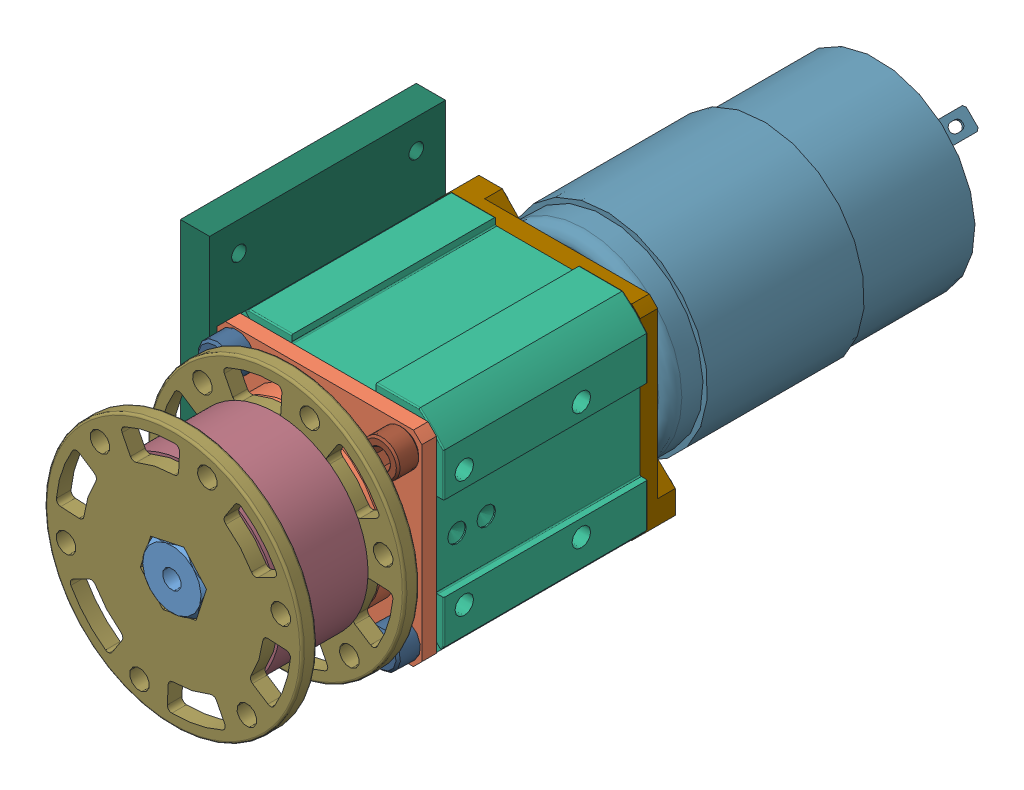
SolidWorks assembly 40-502 Ramp Motor Asm, configuration Default. Lengths in mm.
Overall size (70.41 73.03 162.19).
25 component instances, 15 part files, 20 mates.
Components (placement in the parent):
- 40-501-16 to 1- 57 Sport-1: 40-501-16 to 1- 57 Sport [Default] at (-0.3401 43.5599 88.1883) size (47.68 47.68 89.15) (flexible)
  - am-XXXX - 57 Sport 500 Hex Output Plug-1: am-XXXX - 57 Sport 500 Hex Output Plug [Default] at (20.4435 33.6564 37.638) size (44.45 44.45 56.9) (flexible)
    - am-XXXX - 57 Sport 500 Hex Shaft-1: am-XXXX - 57 Sport 500 Hex Shaft [Default] at (0 0 6.2738) x (0.669193 -0.743089 0) z (0 0 1) size (16.1 12.67 56.9)
    - Output Block-1: Output Block [Default] at origin size (44.45 44.45 20.32)
    - FR8ZZ Bearing-1: FR8ZZ Bearing [Default] at (8.9053 -5.9773 -13.8938) x (0.999973 0.007281 0) z (0 0 1) size (31.75 31.75 7.95)
    - FR8ZZ Bearing-2: FR8ZZ Bearing [Default] at (5.8713 8.9755 6.2738) x (0.923728 0.383049 0) z (0 0 -1) size (31.75 31.75 7.95)
    - retaining Ring 0500 - Mcm 98410A122_98410A122-1: retaining Ring 0500 - Mcm 98410A122_98410A122 [Default] at (0 0 -14.3891) x (0 0 1) z (-0.999848 0.017452 0) size (0.89 16.1 14.34)
  - Thrust washer - 775 Sport-1: Thrust washer - 775 Sport [Default] at (20.4435 33.6564 -8.3472) x (0.883389 0.46864 0) z (0 0 1) size (31 31 1.52)
  - am-XXXX - 57 Sport 2 Stage Ring Gear Housing-1: am-XXXX - 57 Sport 2 Stage Ring Gear Housing [Default] at (20.4435 33.6564 12.365) size (47.68 47.68 44.22)
  - 4_1 Output Stage-1: 4_1 Output Stage [Default] at (-121.0068 37.1623 87.4176) x (-0.999982 -0.006056 0) z (0 0 -1) size (38.96 38.96 14.52)
    - 4_1 Output Stage Carrier Plate-1: 4_1 Output Stage Carrier Plate [Default] at (-141.4265 -4.3625 67.1279) size (30.99 30.99 14.52)
    - 16T Short Planet Gear-1: 16T Short Planet Gear [Default] at (-155.2063 -5.4237 83.0693) x (0 0 1) z (0.923728 0.383049 0) size (7 12.42 12.42)
    - 16T Short Planet Gear-2: 16T Short Planet Gear [Default] at (-142.4877 9.4173 83.0693) x (0 0 1) z (0.383049 -0.923728 0) size (7 12.42 12.42)
    - 16T Short Planet Gear-3: 16T Short Planet Gear [Default] at (-127.6467 -3.3013 83.0693) x (0 0 1) z (-0.923728 -0.383049 0) size (7 12.42 12.42)
    - 16T Short Planet Gear-4: 16T Short Planet Gear [Default] at (-140.3653 -18.1423 83.0693) x (0 0 1) z (-0.383049 0.923728 0) size (7 12.42 12.42)
  - am-3765 - 57 Sport Motor Block-1: am-3765 - 57 Sport Motor Block [Default] at (20.4435 33.6564 -13.543) x (0 1 0) z (0 0 1) size (45.76 47.07 8.89)
  - 10-32x2250_shcs_HX-SHCS 0.19-32x1.375x1-C-1: 10-32x2250_shcs_HX-SHCS 0.19-32x1.375x1-C [Default] at (38.404 15.6959 42.464) x (0 0 -1) z (-0.923728 -0.383049 0) size (61.98 7.94 7.94)
  - 10-32x2250_shcs_HX-SHCS 0.19-32x1.375x1-C-2: 10-32x2250_shcs_HX-SHCS 0.19-32x1.375x1-C [Default] at (2.483 51.6169 42.464) x (0 0 -1) z (-0.85131 -0.524663 0) size (61.98 7.94 7.94)
  - 10-32 X 375 SHCS_90128A940-1: 10-32 X 375 SHCS_90128A940 [Default] at (38.404 51.6169 28.113) x (0.317538 -0.948246 0) z (0 0 -1) size (7.92 7.92 14.58)
  - 10-32 X 375 SHCS_90128A940-2: 10-32 X 375 SHCS_90128A940 [Default] at (2.483 15.6959 28.113) x (0.463868 -0.885904 0) z (0 0 -1) size (7.92 7.92 14.58)
- 10-425 0.5 Hex_Bore_Aluminum_VersaHub_217-2592-1: 10-425 0.5 Hex_Bore_Aluminum_VersaHub_217-2592 [Default] at (20.1034 77.2162 144.8001) x (0 0 -1) z (0.207994 -0.97813 0) size (12.7 55.88 55.88)
- 10-425 0.5 Hex_Bore_Aluminum_VersaHub_217-2592-2: 10-425 0.5 Hex_Bore_Aluminum_VersaHub_217-2592 [Default] at (20.1034 77.2162 144.8001) x (0 0 1) z (-0.951082 0.308937 0) size (12.7 55.88 55.88)
- Part2^40-502 Ramp Motor Asm-1: Part2^40-502 Ramp Motor Asm [Default] at (20.1034 77.2162 135.2751) x (0.207994 -0.97813 0) z (0 0 1) size (40 40 19.05) (virtual)
- 40-500 775pro Motor-1: 40-500 775pro Motor [Default] at (20.1034 77.2162 70.8353) x (0 0 -1) z (0.707107 -0.707107 0) size (88 44.3 44.3)
- Part4^40-502 Ramp Motor Asm-1: Part4^40-502 Ramp Motor Asm [Default] x (1 0 0) z (0 1 0) size (6.35 51.18 73.03) (virtual)
Mates (geometry in assembly coordinates):
- Coincident1: coincident anti-aligned: circle of 10-425 0.5 Hex_Bore_Aluminum_VersaHub_217-2592-1; circle of 10-425 0.5 Hex_Bore_Aluminum_VersaHub_217-2592-2
- Concentric1: concentric aligned: circle of 40-501-16 to 1- 57 Sport-1/am-XXXX - 57 Sport 500 Hex Output Plug-1/am-XXXX - 57 Sport 500 Hex Shaft-1; circle of 10-425 0.5 Hex_Bore_Aluminum_VersaHub_217-2592-1
- Coincident2: coincident anti-aligned: plane of 40-501-16 to 1- 57 Sport-1/am-XXXX - 57 Sport 500 Hex Output Plug-1/FR8ZZ Bearing-2 through (20.1034 77.2162 132.1001) normal (0 0 1); plane of 10-425 0.5 Hex_Bore_Aluminum_VersaHub_217-2592-1 through (50.9603 83.7778 132.1001) normal (0 0 -1)
- Parallel1: parallel anti-aligned: plane of 40-501-16 to 1- 57 Sport-1/am-XXXX - 57 Sport 500 Hex Output Plug-1/am-XXXX - 57 Sport 500 Hex Shaft-1 through (17.8427 70.2565 157.8303) normal (0.207994 -0.97813 0); plane of 10-425 0.5 Hex_Bore_Aluminum_VersaHub_217-2592-2 through (17.8337 70.2286 144.8001) normal (-0.207994 0.97813 0)
- Concentric2: concentric anti-aligned: cylinder of 10-425 0.5 Hex_Bore_Aluminum_VersaHub_217-2592-1 through (43.3952 82.1691 217.8935) axis (0 0 -1) radius 2.15; cylinder of 10-425 0.5 Hex_Bore_Aluminum_VersaHub_217-2592-2 through (43.3952 82.1691 71.7067) axis (0 0 1) radius 2.15
- InPlace1: in place: plane of ? through (-5.2278 96.0186 157.5001) normal (0 0 1); plane of ? through (0 0 157.5001) normal (0 0 1); moOrthogonalPlaneRef_w of ? through (-5.2278 96.0186 157.5001) normal (0 0 1); plane of ? through (0 0 157.5001) normal (0 1 0); plane of ? through (-5.2278 96.0186 157.5001) normal (0 0 1); plane of ? through (0 0 157.5001) normal (1 0 0); plane of ? through (-5.2278 96.0186 157.5001) normal (0 0 1); unknown of ?
- Coincident4: coincident aligned: plane of 10-425 0.5 Hex_Bore_Aluminum_VersaHub_217-2592-2; plane of ?
- Coincident5: coincident aligned: moOrthogonalPlaneRef_w of 10-425 0.5 Hex_Bore_Aluminum_VersaHub_217-2592-2 through (20.1034 77.2162 157.5001) normal (-0.802974 0.596014 0); plane of ? through (20.1034 77.2162 157.5001) normal (-0.802974 0.596014 0)
- Coincident6: coincident anti-aligned: moOrthogonalPlaneRef_w of 10-425 0.5 Hex_Bore_Aluminum_VersaHub_217-2592-2 through (20.1034 77.2162 157.5001) normal (-0.596014 -0.802974 0); plane of ? through (20.1034 77.2162 157.5001) normal (0.596014 0.802974 0)
- InPlace2: in place: plane of ? through (21.7427 91.4169 135.2751) normal (0 0 1); plane of ? through (0 0 135.2751) normal (0 0 1); plane of ? through (21.7427 91.4169 135.2751) normal (0 0 1); plane of ? through (0 0 135.2751) normal (0 1 0); plane of ? through (21.7427 91.4169 135.2751) normal (0 0 1); plane of ? through (0 0 135.2751) normal (1 0 0); plane of 10-425 0.5 Hex_Bore_Aluminum_VersaHub_217-2592-1 through (34.0857 80.1895 135.2751) normal (0 0 1); unknown of Part2^40-502 Ramp Motor Asm-1
- Coincident7: coincident aligned: plane of 10-425 0.5 Hex_Bore_Aluminum_VersaHub_217-2592-1 through (34.0857 80.1895 135.2751) normal (0 0 1); plane of Part2^40-502 Ramp Motor Asm-1 through (20.1034 77.2162 135.2751) normal (0 0 1)
- Coincident8: coincident aligned: moOrthogonalPlaneRef_w of 10-425 0.5 Hex_Bore_Aluminum_VersaHub_217-2592-1; plane of Part2^40-502 Ramp Motor Asm-1 through (20.1034 77.2162 135.2751) normal (0.97813 0.207994 0)
- Coincident9: coincident anti-aligned: moOrthogonalPlaneRef_w of 10-425 0.5 Hex_Bore_Aluminum_VersaHub_217-2592-1; plane of Part2^40-502 Ramp Motor Asm-1 through (20.1034 77.2162 135.2751) normal (0.207994 -0.97813 0)
- Concentric3: concentric anti-aligned: cylinder of 40-501-16 to 1- 57 Sport-1/am-3765 - 57 Sport Motor Block-1 through (20.1034 77.2162 70.8353) axis (0 0 -1) radius 8.7757; cylinder of 40-500 775pro Motor-1 through (20.1034 77.2162 70.8353) axis (0 0 1) radius 2.5
- Concentric7: concentric aligned: cylinder of 40-501-16 to 1- 57 Sport-1/am-3765 - 57 Sport Motor Block-1 through (30.3565 87.4693 79.7253) axis (0 0 1) radius 2.25; cylinder of 40-500 775pro Motor-1 through (30.3565 87.4693 70.8353) axis (0 0 1) radius 1.65
- Coincident11: coincident anti-aligned: plane of 40-501-16 to 1- 57 Sport-1/am-3765 - 57 Sport Motor Block-1 through (20.1034 77.2162 70.8353) normal (0 0 -1); plane of 40-500 775pro Motor-1 through (26.3967 83.5095 70.8353) normal (0 0 1)
- InPlace3: in place: plane of Part4^40-502 Ramp Motor Asm-1 through (0 0 0) normal (0 1 0); plane of Part4^40-502 Ramp Motor Asm-1 through (0 0 0) normal (0 0 -1); plane of Part4^40-502 Ramp Motor Asm-1 through (0 0 0) normal (1 0 0); unknown of Part4^40-502 Ramp Motor Asm-1
- Coincident12: coincident aligned: plane of Part4^40-502 Ramp Motor Asm-1; plane of assembly
- Coincident13: coincident aligned: plane of Part4^40-502 Ramp Motor Asm-1 through (0 0 0) normal (0 0 -1); moOrthogonalPlaneRef_w of assembly
- Coincident14: coincident anti-aligned: plane of Part4^40-502 Ramp Motor Asm-1 through (0 0 0) normal (1 0 0); moOrthogonalPlaneRef_w of assembly
